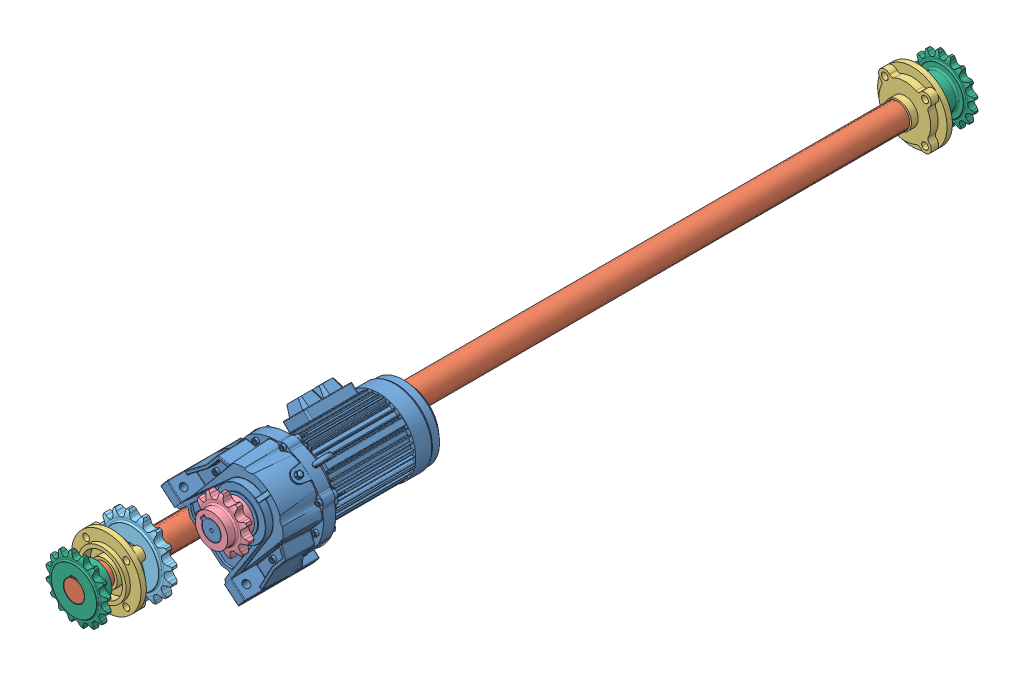
SolidWorks assembly 提升装置, configuration Default. Lengths in mm.
Overall size (591.39 549.02 2462.01).
8 component instances, 6 part files, 15 mates.
Components (placement in the parent):
- JNAP-50DX-3.7KW-55(1)-1: JNAP-50DX-3.7KW-55(1) [默认] at (5943.6455 1729.4528 1179.4605) x (-0.766024 0.642812 0.000028) z (-0.000036 0 -1) size (290.36 323.17 577)
- 提升轴-1: 提升轴 [默认] at (5785.5363 1533.6781 -998.5877) x (-0.923728 -0.383049 0.000033) z (-0.000036 0 -1) size (70 70 2461)
- 轴承UK212-1: 轴承UK212 [默认] at (5785.5396 1533.6781 -908.0927) x (0.707084 -0.70713 -0.000025) z (0.000036 0 1) size (195 195 67)
- 轴承UK212-2: 轴承UK212 [默认] at (5785.6217 1533.6783 1371.9073) x (-0.70713 -0.707084 0.000026) z (-0.000036 0 -1) size (195 195 67)
- 单排链轮1  24A-11-1: 单排链轮1  24A-11 [24A] at (6031.1521 1732.8832 1284.3989) x (0.000036 0 1) z (-0.642812 -0.766024 0.000023) size (75 147.86 149.3)
- 单排链轮24A-16-1: 单排链轮24A-16 [24A] at (5785.6185 1533.6783 1284.4078) x (0.000036 0 1) z (-0.999966 0.008226 0.000036) size (33.99 209 209)
- 单排链轮20A-16-1: 单排链轮20A-16 [20A] at (5785.6245 1533.6783 1449.761) x (0.000036 0 1) z (-1 0 0.000036) size (60 173.53 173.53)
- 单排链轮20A-16-2: 单排链轮20A-16 [20A] at (5785.5368 1533.6781 -985.9365) x (-0.000036 0 -1) z (-0.923727 -0.383053 0.000033) size (60 173.53 173.53)
Mates (geometry in assembly coordinates):
- 同心120: concentric: cylinder of 提升轴-1 through (5785.5363 1533.6781 -998.5877) axis (-0.000036 0 -1) radius 30; cylinder of 轴承UK212-1 through (5785.5392 1533.6781 -920.0937) axis (0.000036 0 1) radius 30
- 同心118: concentric: cylinder of 提升轴-1 through (5785.5363 1533.6781 -998.5877) axis (-0.000036 0 -1) radius 30; cylinder of 轴承UK212-2 through (5785.6221 1533.6783 1383.9083) axis (-0.000036 0 -1) radius 30
- 同心119: concentric: cylinder of 提升轴-1 through (5785.5363 1533.6781 -998.5877) axis (-0.000036 0 -1) radius 30; cylinder of 轴承UK212-2 through (5785.6221 1533.6783 1383.9083) axis (-0.000036 0 -1) radius 30
- 同心117: concentric: cylinder of JNAP-50DX-3.7KW-55(1)-1 through (6031.1507 1732.8832 1246.8983) axis (0.000036 0 1) radius 27.5; cylinder of 单排链轮1  24A-11-1 through (6031.1514 1732.8832 1266.9173) axis (0.000036 0 1) radius 27.5
- 平行18: parallel: plane of JNAP-50DX-3.7KW-55(1)-1 through (6009.5414 1740.5755 1321.899) normal (-0.642812 -0.766024 0.000023); plane of 单排链轮1  24A-11-1 through (6013.8758 1735.6312 1266.9189) normal (0.642812 0.766024 -0.000023)
- 同心121: concentric: cylinder of 提升轴-1 through (5785.5363 1533.6781 -998.5877) axis (-0.000036 0 -1) radius 30; cylinder of 单排链轮24A-16-1 through (5785.6179 1533.6783 1267.4113) axis (0.000036 0 1) radius 30
- 重合215: coincident: plane of 提升轴-1 through (5772.2112 1566.0088 1267.4127) normal (0.000036 0 1); plane of 单排链轮24A-16-1 through (5785.6179 1533.6783 1267.4123) normal (-0.000036 0 -1)
- 重合218: coincident: plane of 单排链轮1  24A-11-1 through (5987.8704 1769.2036 1296.38) normal (0.000036 0 1); plane of 单排链轮24A-16-1 through (5786.3308 1620.2075 1296.3873) normal (0.000036 0 1)
- 重合219: coincident: plane of JNAP-50DX-3.7KW-55(1)-1 through (6031.1507 1732.8832 1246.8983) normal (0.000036 0 1); plane of 单排链轮1  24A-11-1 through (6031.1507 1732.8832 1246.8983) normal (-0.000036 0 -1)
- 距离1: distance = 2280 mm: plane of 轴承UK212-2 through (5785.6217 1533.6783 1371.9073) normal (0.000036 0 1); plane of 轴承UK212-1 through (5785.5396 1533.6781 -908.0927) normal (-0.000036 0 -1)
- 同心122: concentric: cylinder of 提升轴-1 through (5785.5363 1533.6781 -998.5877) axis (-0.000036 0 -1) radius 30; cylinder of 单排链轮20A-16-2 through (5785.5373 1533.6781 -972.7842) axis (-0.000036 0 -1) radius 30
- 同心123: concentric: cylinder of 提升轴-1 through (5785.5363 1533.6781 -998.5877) axis (-0.000036 0 -1) radius 30; cylinder of 单排链轮20A-16-1 through (5785.624 1533.6783 1436.6087) axis (0.000036 0 1) radius 30
- 距离2: distance = 0.5 mm: plane of 单排链轮20A-16-1 through (5785.625 1597.1783 1462.9122) normal (0.000036 0 1); plane of 提升轴-1 through (5774.1335 1561.3902 1462.4127) normal (0.000036 0 1)
- 距离4: distance = 0.5 mm: plane of 提升轴-1 through (5785.5363 1533.6781 -998.5877) normal (-0.000036 0 -1); plane of 单排链轮20A-16-2 through (5809.8602 1475.0214 -999.0886) normal (-0.000036 0 -1)
- 距离5: distance = 75.52 mm: plane of 单排链轮24A-16-1 through (5786.3308 1620.2075 1296.3873) normal (0.000036 0 1); plane of 轴承UK212-2 through (5785.6217 1533.6783 1371.9073) normal (0.000036 0 1)
